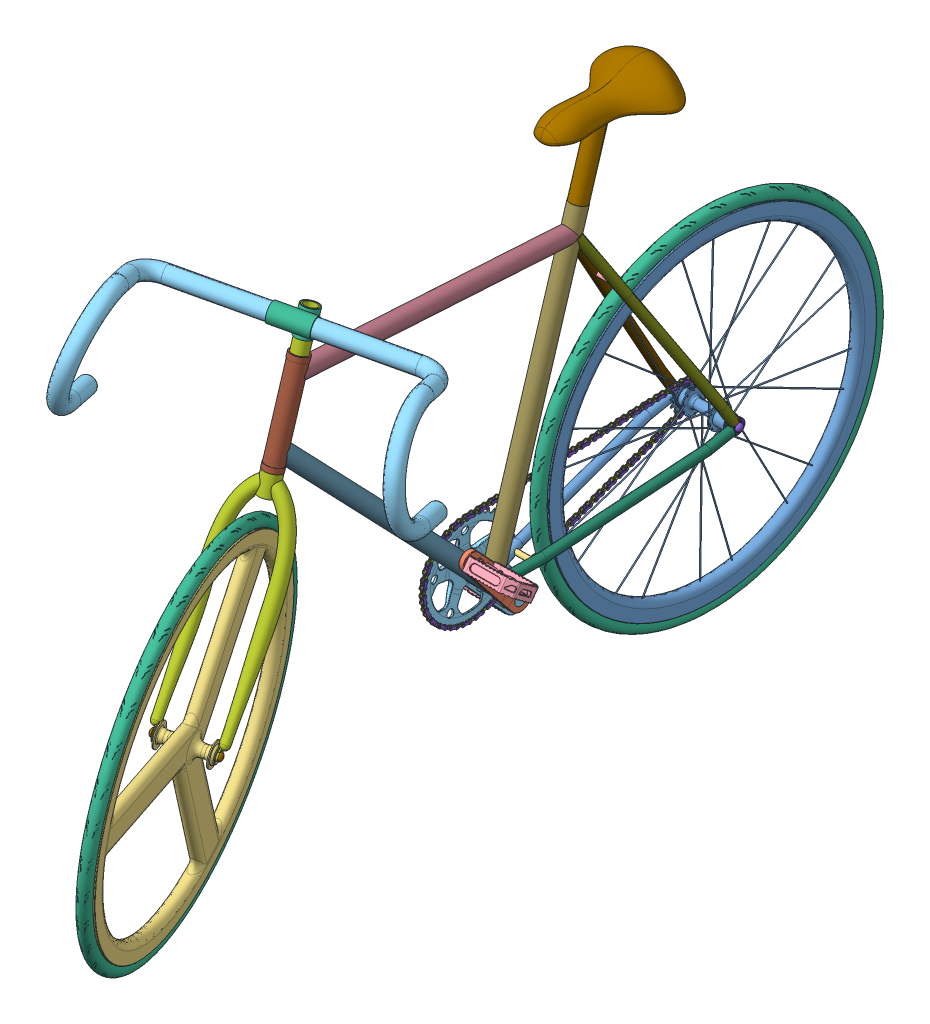
SolidWorks assembly Fixie, configuration Default. Lengths in mm.
Overall size (664.18 1172.49 1914.22).
126 component instances, 27 part files, 33 mates.
Components (placement in the parent):
- Copy of Back Wheel^Fixie-1: Copy of Back Wheel^Fixie [Default] at (-15.95 85.0139 -432.7378) x (1 0 0) z (0 -0.997869 -0.065253) size (100 658.88 658.88) (virtual)
- Copy of Crank 2^Fixie-1: Copy of Crank 2^Fixie [Default] at (48.55 125.8619 140.7881) x (0 0.660802 -0.75056) z (-1 0 0) size (45 210 26.78) (virtual)
- Copy of Front Wheel^Fixie-1: Copy of Front Wheel^Fixie [Default] at (21.1934 60.1847 648.9322) x (0.932997 -0.10522 -0.344158) z (0.342979 0.549615 0.761767) size (100 658.88 658.88) (virtual)
- Copy of Pedal 2^Fixie-1: Copy of Pedal 2^Fixie [Default] at (-152.95 -127.5952 -112.3364) x (0 0.808966 0.587856) z (1 0 0) size (80 25 117.5) (virtual)
- Copy of Sprocket 2^Fixie-1: Copy of Sprocket 2^Fixie [Default] at (-66.45 0 0) x (-1 0 0) z (0 -0.975768 0.218806) size (135 250.05 212.39) (virtual)
- Copy of Tire^Fixie-1: Copy of Tire^Fixie [Default] at (-15.95 85.0139 -432.7378) x (1 0 0) z (0 -0.101006 0.994886) size (24.5 700 700) (virtual)
- Copy of Tire^Fixie-2: Copy of Tire^Fixie [Default] at (21.1934 60.1847 648.9322) x (0.932997 -0.10522 -0.344158) z (0.359683 0.240759 0.901478) size (24.5 700 700) (virtual)
- Copy of fourche^Fixie-1: Copy of fourche^Fixie [Défaut<Brut d'usinage>] at (-16.45 376.3038 450.2354) x (0.932997 -0.10522 -0.344158) z (0.359883 0.272782 0.89223) size (141.09 668.83 129.54) (virtual)
- Copy of Pedal 2^Fixie-2: Copy of Pedal 2^Fixie [Default] at (120.05 127.5952 112.3364) x (0 0.589054 0.808094) z (-1 0 0) size (80 25 117.5) (virtual)
- Copy of Axe 2^Fixie-1: Copy of Axe 2^Fixie [Default] at (-16.45 85.0139 -432.7378) x (1 0 0) z (0 0.986418 0.164253) size (142 15 15) (virtual)
- Copy of Axe^Fixie-1: Copy of Axe^Fixie [Default] at (21.1934 60.1847 648.9322) x (-0.199209 0.645439 -0.737377) z (0.932997 -0.10522 -0.344158) size (15 15 115) (virtual)
- Copy of cadre^Fixie-1: Copy of cadre^Fixie [Défaut] at (-16.45 0 0) size (140 613.27 908.21) (virtual)
  - tube pedalier^Copy of cadre_Fixie-1: tube pedalier^Copy of cadre_Fixie [Défaut] at origin size (73 33 33) (virtual)
  - trou pour fourche^Copy of cadre_Fixie-2: trou pour fourche^Copy of cadre_Fixie [Défaut] at (0 502.9172 411.5258) x (0.998411 0.016475 0.053886) z (0 -0.956305 0.292372) size (35 35 185) (virtual)
  - tube de selle^Copy of cadre_Fixie-1: tube de selle^Copy of cadre_Fixie [Défaut] at (0 573.7829 -175.423) x (1 0 0) z (0 0.956305 -0.292372) size (32.9 32.9 600.3) (virtual)
  - tube de tete^Copy of cadre_Fixie-1: tube de tete^Copy of cadre_Fixie [Défaut] at (0 561.2509 393.6914) x (1 0 0) z (0 0.060491 0.998169) size (32.9 32.9 555.16) (virtual)
  - tube du bas^Copy of cadre_Fixie-3: tube du bas^Copy of cadre_Fixie [Défaut] at (0 447.1547 428.5741) x (-1 0 0) z (0 -0.721947 -0.691948) size (32.9 32.9 618.4) (virtual)
  - tube arriere bas^Copy of cadre_Fixie-2: tube arriere bas^Copy of cadre_Fixie [Défaut] at origin size (67.83 98.35 411.57) (virtual)
  - tube arriere haut^Copy of cadre_Fixie-1: tube arriere haut^Copy of cadre_Fixie [Défaut] at origin size (69.56 441.01 279.99) (virtual)
  - encoche roue^Copy of cadre_Fixie-7: encoche roue^Copy of cadre_Fixie [Défaut] at (61 85.0139 -432.7378) x (0 -0.852467 -0.522781) z (-1 0 0) size (54 61.43 6.25) (virtual)
  - Symétrietube arriere haut^Copy of cadre_Fixie-2: Symétrietube arriere haut^Copy of cadre_Fixie [Défaut] x (-1 0 0) z (0 0 -1) size (69.56 441.01 279.99) (virtual)
  - Symétrietube arriere bas^Copy of cadre_Fixie-3: Symétrietube arriere bas^Copy of cadre_Fixie [Défaut] x (-1 0 0) z (0 0 -1) size (67.83 98.35 411.57) (virtual)
  - Symétrieencoche roue^Copy of cadre_Fixie-8: Symétrieencoche roue^Copy of cadre_Fixie [Défaut] at (-61 85.0139 -432.7378) x (0 -0.852467 -0.522781) z (-1 0 0) size (54 61.43 6.25) (virtual)
  - tube consolider 1^Copy of cadre_Fixie-1: tube consolider 1^Copy of cadre_Fixie [Défaut] x (0 0 -1) z (1 0 0) size (10 10 30.38) (virtual)
  - tube consolider 2^Copy of cadre_Fixie-1: tube consolider 2^Copy of cadre_Fixie [Défaut] x (0 0 -1) z (1 0 0) size (10 10 34.39) (virtual)
- Copy of Guidon 2^Fixie-1: Copy of Guidon 2^Fixie [Défaut] at (6.8353 678.1903 421.0648) x (0.932997 -0.10522 -0.344158) z (0.023583 0.972124 -0.233276) size (595.69 286.25 238.07) (virtual)
- Copy of Potence 2^Fixie-1: Copy of Potence 2^Fixie [Défaut] at (6.8353 678.1903 421.0648) x (-0.359883 -0.272782 -0.89223) z (0.932997 -0.10522 -0.344158) size (98.9 64.61 70) (virtual)
- Copy of Inner Chain^Fixie-1: Copy of Inner Chain^Fixie [Default] at (-62.45 99.4001 -193.872) x (1 0 0) z (0 -0.042605 0.999092) size (5 8 20.8) (virtual)
- Copy of Outter Chain^Fixie-1: Copy of Outter Chain^Fixie [Default] at (-62.45 99.9453 -206.6574) x (1 0 0) z (0 -0.042605 0.999092) size (8.5 8 20.8) (virtual)
- Copy of Inner Chain^Fixie-52: Copy of Inner Chain^Fixie [Default] at (-62.45 100.4905 -219.4428) x (1 0 0) z (0 -0.042605 0.999092) size (5 8 20.8) (virtual)
- Copy of Inner Chain^Fixie-53: Copy of Inner Chain^Fixie [Default] at (-62.45 101.581 -245.0135) x (1 0 0) z (0 -0.042605 0.999092) size (5 8 20.8) (virtual)
- Copy of Inner Chain^Fixie-54: Copy of Inner Chain^Fixie [Default] at (-62.45 102.6714 -270.5843) x (1 0 0) z (0 -0.042605 0.999092) size (5 8 20.8) (virtual)
- Copy of Inner Chain^Fixie-55: Copy of Inner Chain^Fixie [Default] at (-62.45 103.7618 -296.155) x (1 0 0) z (0 -0.042605 0.999092) size (5 8 20.8) (virtual)
- Copy of Inner Chain^Fixie-56: Copy of Inner Chain^Fixie [Default] at (-62.45 104.8523 -321.7258) x (1 0 0) z (0 -0.042605 0.999092) size (5 8 20.8) (virtual)
- Copy of Inner Chain^Fixie-57: Copy of Inner Chain^Fixie [Default] at (-62.45 105.9427 -347.2966) x (1 0 0) z (0 -0.042605 0.999092) size (5 8 20.8) (virtual)
- Copy of Inner Chain^Fixie-58: Copy of Inner Chain^Fixie [Default] at (-62.45 107.0331 -372.8673) x (1 0 0) z (0 -0.042605 0.999092) size (5 8 20.8) (virtual)
- Copy of Inner Chain^Fixie-59: Copy of Inner Chain^Fixie [Default] at (-62.45 108.1235 -398.4381) x (1 0 0) z (0 -0.042605 0.999092) size (5 8 20.8) (virtual)
- Copy of Inner Chain^Fixie-60: Copy of Inner Chain^Fixie [Default] at (-62.45 109.214 -424.0088) x (1 0 0) z (0 -0.042605 0.999092) size (5 8 20.8) (virtual)
- Copy of Inner Chain^Fixie-61: Copy of Inner Chain^Fixie [Default] at (-62.45 103.2107 -447.9246) x (1 0 0) z (0 0.640753 0.767747) size (5 8 20.8) (virtual)
- Copy of Inner Chain^Fixie-62: Copy of Inner Chain^Fixie [Default] at (-62.45 80.7849 -456.059) x (1 0 0) z (0 0.983953 -0.178426) size (5 8 20.8) (virtual)
- Copy of Inner Chain^Fixie-63: Copy of Inner Chain^Fixie [Default] at (-62.45 62.2217 -440.7328) x (1 0 0) z (0 0.396262 -0.918137) size (5 8 20.8) (virtual)
- Copy of Inner Chain^Fixie-64: Copy of Inner Chain^Fixie [Default] at (-62.45 53.188 -416.796) x (1 0 0) z (0 0.338529 -0.940956) size (5 8 20.8) (virtual)
- Copy of Inner Chain^Fixie-65: Copy of Inner Chain^Fixie [Default] at (-62.45 44.5237 -392.7132) x (1 0 0) z (0 0.338529 -0.940956) size (5 8 20.8) (virtual)
- Copy of Inner Chain^Fixie-66: Copy of Inner Chain^Fixie [Default] at (-62.45 35.8594 -368.6303) x (1 0 0) z (0 0.338529 -0.940956) size (5 8 20.8) (virtual)
- Copy of Inner Chain^Fixie-67: Copy of Inner Chain^Fixie [Default] at (-62.45 27.195 -344.5475) x (1 0 0) z (0 0.338529 -0.940956) size (5 8 20.8) (virtual)
- Copy of Inner Chain^Fixie-68: Copy of Inner Chain^Fixie [Default] at (-62.45 18.5307 -320.4647) x (1 0 0) z (0 0.338529 -0.940956) size (5 8 20.8) (virtual)
- Copy of Inner Chain^Fixie-69: Copy of Inner Chain^Fixie [Default] at (-62.45 9.8664 -296.3818) x (1 0 0) z (0 0.338529 -0.940956) size (5 8 20.8) (virtual)
- Copy of Inner Chain^Fixie-70: Copy of Inner Chain^Fixie [Default] at (-62.45 1.2021 -272.299) x (1 0 0) z (0 0.338529 -0.940956) size (5 8 20.8) (virtual)
- Copy of Inner Chain^Fixie-71: Copy of Inner Chain^Fixie [Default] at (-62.45 -7.4622 -248.2162) x (1 0 0) z (0 0.338529 -0.940956) size (5 8 20.8) (virtual)
- Copy of Inner Chain^Fixie-72: Copy of Inner Chain^Fixie [Default] at (-62.45 -16.1265 -224.1334) x (1 0 0) z (0 0.338529 -0.940956) size (5 8 20.8) (virtual)
- Copy of Inner Chain^Fixie-73: Copy of Inner Chain^Fixie [Default] at (-62.45 -24.7908 -200.0505) x (1 0 0) z (0 0.338529 -0.940956) size (5 8 20.8) (virtual)
- Copy of Inner Chain^Fixie-74: Copy of Inner Chain^Fixie [Default] at (-62.45 -33.4551 -175.9677) x (1 0 0) z (0 0.338529 -0.940956) size (5 8 20.8) (virtual)
- Copy of Inner Chain^Fixie-75: Copy of Inner Chain^Fixie [Default] at (-62.45 -42.1195 -151.8849) x (1 0 0) z (0 0.338529 -0.940956) size (5 8 20.8) (virtual)
- Copy of Inner Chain^Fixie-76: Copy of Inner Chain^Fixie [Default] at (-62.45 -50.7838 -127.8021) x (1 0 0) z (0 0.338529 -0.940956) size (5 8 20.8) (virtual)
- Copy of Inner Chain^Fixie-77: Copy of Inner Chain^Fixie [Default] at (-62.45 -59.4481 -103.7192) x (1 0 0) z (0 0.338529 -0.940956) size (5 8 20.8) (virtual)
- Copy of Inner Chain^Fixie-78: Copy of Inner Chain^Fixie [Default] at (-62.45 -68.1124 -79.6364) x (1 0 0) z (0 0.338529 -0.940956) size (5 8 20.8) (virtual)
- Copy of Inner Chain^Fixie-79: Copy of Inner Chain^Fixie [Default] at (-62.45 -76.7767 -55.5536) x (1 0 0) z (0 0.338529 -0.940956) size (5 8 20.8) (virtual)
- Copy of Inner Chain^Fixie-80: Copy of Inner Chain^Fixie [Default] at (-62.45 -85.3565 -31.441) x (1 0 0) z (0 0.325323 -0.945603) size (5 8 20.8) (virtual)
- Copy of Inner Chain^Fixie-81: Copy of Inner Chain^Fixie [Default] at (-62.45 -90.5921 -6.4987) x (1 0 0) z (0 0.071552 -0.997437) size (5 8 20.8) (virtual)
- Copy of Inner Chain^Fixie-82: Copy of Inner Chain^Fixie [Default] at (-62.45 -88.8349 18.9082) x (1 0 0) z (0 -0.208183 -0.97809) size (5 8 20.8) (virtual)
- Copy of Inner Chain^Fixie-83: Copy of Inner Chain^Fixie [Default] at (-62.45 -80.093 42.8284) x (1 0 0) z (0 -0.471549 -0.88184) size (5 8 20.8) (virtual)
- Copy of Inner Chain^Fixie-84: Copy of Inner Chain^Fixie [Default] at (-62.45 -65.0537 63.3812) x (1 0 0) z (0 -0.69784 -0.716254) size (5 8 20.8) (virtual)
- Copy of Inner Chain^Fixie-85: Copy of Inner Chain^Fixie [Default] at (-62.45 -44.8995 78.9506) x (1 0 0) z (0 -0.869262 -0.494352) size (5 8 20.8) (virtual)
- Copy of Inner Chain^Fixie-86: Copy of Inner Chain^Fixie [Default] at (-62.45 -21.215 88.3124) x (1 0 0) z (0 -0.972337 -0.233581) size (5 8 20.8) (virtual)
- Copy of Inner Chain^Fixie-87: Copy of Inner Chain^Fixie [Default] at (-62.45 4.1376 90.7306) x (1 0 0) z (0 -0.998962 0.045555) size (5 8 20.8) (virtual)
- Copy of Inner Chain^Fixie-88: Copy of Inner Chain^Fixie [Default] at (-62.45 29.1648 86.015) x (1 0 0) z (0 -0.947042 0.32111) size (5 8 20.8) (virtual)
- Copy of Inner Chain^Fixie-89: Copy of Inner Chain^Fixie [Default] at (-62.45 51.8989 74.5363) x (1 0 0) z (0 -0.82066 0.571417) size (5 8 20.8) (virtual)
- Copy of Inner Chain^Fixie-90: Copy of Inner Chain^Fixie [Default] at (-62.45 70.5524 57.1972) x (1 0 0) z (0 -0.629752 0.776796) size (5 8 20.8) (virtual)
- Copy of Inner Chain^Fixie-91: Copy of Inner Chain^Fixie [Default] at (-62.45 83.6587 35.3609) x (1 0 0) z (0 -0.38933 0.921098) size (5 8 20.8) (virtual)
- Copy of Inner Chain^Fixie-92: Copy of Inner Chain^Fixie [Default] at (-62.45 90.1872 10.7443) x (1 0 0) z (0 -0.118296 0.992978) size (5 8 20.8) (virtual)
- Copy of Inner Chain^Fixie-93: Copy of Inner Chain^Fixie [Default] at (-62.45 91.7633 -14.7873) x (1 0 0) z (0 -0.042605 0.999092) size (5 8 20.8) (virtual)
- Copy of Inner Chain^Fixie-94: Copy of Inner Chain^Fixie [Default] at (-62.45 92.8538 -40.3581) x (1 0 0) z (0 -0.042605 0.999092) size (5 8 20.8) (virtual)
- Copy of Inner Chain^Fixie-95: Copy of Inner Chain^Fixie [Default] at (-62.45 93.9442 -65.9288) x (1 0 0) z (0 -0.042605 0.999092) size (5 8 20.8) (virtual)
- Copy of Inner Chain^Fixie-96: Copy of Inner Chain^Fixie [Default] at (-62.45 95.0346 -91.4996) x (1 0 0) z (0 -0.042605 0.999092) size (5 8 20.8) (virtual)
- Copy of Inner Chain^Fixie-97: Copy of Inner Chain^Fixie [Default] at (-62.45 96.125 -117.0704) x (1 0 0) z (0 -0.042605 0.999092) size (5 8 20.8) (virtual)
- Copy of Inner Chain^Fixie-98: Copy of Inner Chain^Fixie [Default] at (-62.45 97.2155 -142.6411) x (1 0 0) z (0 -0.042605 0.999092) size (5 8 20.8) (virtual)
- Copy of Outter Chain^Fixie-52: Copy of Outter Chain^Fixie [Default] at (-62.45 101.0358 -232.2281) x (1 0 0) z (0 -0.042605 0.999092) size (8.5 8 20.8) (virtual)
- Copy of Outter Chain^Fixie-53: Copy of Outter Chain^Fixie [Default] at (-62.45 102.1262 -257.7989) x (1 0 0) z (0 -0.042605 0.999092) size (8.5 8 20.8) (virtual)
- Copy of Outter Chain^Fixie-54: Copy of Outter Chain^Fixie [Default] at (-62.45 103.2166 -283.3697) x (1 0 0) z (0 -0.042605 0.999092) size (8.5 8 20.8) (virtual)
- Copy of Outter Chain^Fixie-55: Copy of Outter Chain^Fixie [Default] at (-62.45 104.307 -308.9404) x (1 0 0) z (0 -0.042605 0.999092) size (8.5 8 20.8) (virtual)
- Copy of Outter Chain^Fixie-56: Copy of Outter Chain^Fixie [Default] at (-62.45 105.3975 -334.5112) x (1 0 0) z (0 -0.042605 0.999092) size (8.5 8 20.8) (virtual)
- Copy of Outter Chain^Fixie-57: Copy of Outter Chain^Fixie [Default] at (-62.45 106.4879 -360.0819) x (1 0 0) z (0 -0.042605 0.999092) size (8.5 8 20.8) (virtual)
- Copy of Outter Chain^Fixie-58: Copy of Outter Chain^Fixie [Default] at (-62.45 107.5783 -385.6527) x (1 0 0) z (0 -0.042605 0.999092) size (8.5 8 20.8) (virtual)
- Copy of Outter Chain^Fixie-59: Copy of Outter Chain^Fixie [Default] at (-62.45 108.6687 -411.2235) x (1 0 0) z (0 -0.042605 0.999092) size (8.5 8 20.8) (virtual)
- Copy of Outter Chain^Fixie-60: Copy of Outter Chain^Fixie [Default] at (-62.45 108.3985 -436.7069) x (1 0 0) z (0 0.170044 0.985436) size (8.5 8 20.8) (virtual)
- Copy of Outter Chain^Fixie-61: Copy of Outter Chain^Fixie [Default] at (-62.45 93.0958 -455.0188) x (1 0 0) z (0 0.940068 0.340986) size (8.5 8 20.8) (virtual)
- Copy of Outter Chain^Fixie-62: Copy of Outter Chain^Fixie [Default] at (-62.45 69.6231 -450.7624) x (1 0 0) z (0 0.760484 -0.649357) size (8.5 8 20.8) (virtual)
- Copy of Outter Chain^Fixie-63: Copy of Outter Chain^Fixie [Default] at (-62.45 57.5201 -428.8374) x (1 0 0) z (0 0.338529 -0.940956) size (8.5 8 20.8) (virtual)
- Copy of Outter Chain^Fixie-64: Copy of Outter Chain^Fixie [Default] at (-62.45 48.8558 -404.7546) x (1 0 0) z (0 0.338529 -0.940956) size (8.5 8 20.8) (virtual)
- Copy of Outter Chain^Fixie-65: Copy of Outter Chain^Fixie [Default] at (-62.45 40.1915 -380.6717) x (1 0 0) z (0 0.338529 -0.940956) size (8.5 8 20.8) (virtual)
- Copy of Outter Chain^Fixie-66: Copy of Outter Chain^Fixie [Default] at (-62.45 31.5272 -356.5889) x (1 0 0) z (0 0.338529 -0.940956) size (8.5 8 20.8) (virtual)
- Copy of Outter Chain^Fixie-67: Copy of Outter Chain^Fixie [Default] at (-62.45 22.8629 -332.5061) x (1 0 0) z (0 0.338529 -0.940956) size (8.5 8 20.8) (virtual)
- Copy of Outter Chain^Fixie-68: Copy of Outter Chain^Fixie [Default] at (-62.45 14.1986 -308.4233) x (1 0 0) z (0 0.338529 -0.940956) size (8.5 8 20.8) (virtual)
- Copy of Outter Chain^Fixie-69: Copy of Outter Chain^Fixie [Default] at (-62.45 5.5343 -284.3404) x (1 0 0) z (0 0.338529 -0.940956) size (8.5 8 20.8) (virtual)
- Copy of Outter Chain^Fixie-70: Copy of Outter Chain^Fixie [Default] at (-62.45 -3.1301 -260.2576) x (1 0 0) z (0 0.338529 -0.940956) size (8.5 8 20.8) (virtual)
- Copy of Outter Chain^Fixie-71: Copy of Outter Chain^Fixie [Default] at (-62.45 -11.7944 -236.1748) x (1 0 0) z (0 0.338529 -0.940956) size (8.5 8 20.8) (virtual)
- Copy of Outter Chain^Fixie-72: Copy of Outter Chain^Fixie [Default] at (-62.45 -20.4587 -212.092) x (1 0 0) z (0 0.338529 -0.940956) size (8.5 8 20.8) (virtual)
- Copy of Outter Chain^Fixie-73: Copy of Outter Chain^Fixie [Default] at (-62.45 -29.123 -188.0091) x (1 0 0) z (0 0.338529 -0.940956) size (8.5 8 20.8) (virtual)
- Copy of Outter Chain^Fixie-74: Copy of Outter Chain^Fixie [Default] at (-62.45 -37.7873 -163.9263) x (1 0 0) z (0 0.338529 -0.940956) size (8.5 8 20.8) (virtual)
- Copy of Outter Chain^Fixie-75: Copy of Outter Chain^Fixie [Default] at (-62.45 -46.4516 -139.8435) x (1 0 0) z (0 0.338529 -0.940956) size (8.5 8 20.8) (virtual)
- Copy of Outter Chain^Fixie-76: Copy of Outter Chain^Fixie [Default] at (-62.45 -55.1159 -115.7606) x (1 0 0) z (0 0.338529 -0.940956) size (8.5 8 20.8) (virtual)
- Copy of Outter Chain^Fixie-77: Copy of Outter Chain^Fixie [Default] at (-62.45 -63.7802 -91.6778) x (1 0 0) z (0 0.338529 -0.940956) size (8.5 8 20.8) (virtual)
- Copy of Outter Chain^Fixie-78: Copy of Outter Chain^Fixie [Default] at (-62.45 -72.4446 -67.595) x (1 0 0) z (0 0.338529 -0.940956) size (8.5 8 20.8) (virtual)
- Copy of Outter Chain^Fixie-79: Copy of Outter Chain^Fixie [Default] at (-62.45 -81.1089 -43.5122) x (1 0 0) z (0 0.338529 -0.940956) size (8.5 8 20.8) (virtual)
- Copy of Outter Chain^Fixie-80: Copy of Outter Chain^Fixie [Default] at (-62.45 -88.7862 -19.1357) x (1 0 0) z (0 0.210688 -0.977553) size (8.5 8 20.8) (virtual)
- Copy of Outter Chain^Fixie-81: Copy of Outter Chain^Fixie [Default] at (-62.45 -90.6084 6.2666) x (1 0 0) z (0 -0.068997 -0.997617) size (8.5 8 20.8) (virtual)
- Copy of Outter Chain^Fixie-82: Copy of Outter Chain^Fixie [Default] at (-62.45 -85.3065 31.1762) x (1 0 0) z (0 -0.343256 -0.939242) size (8.5 8 20.8) (virtual)
- Copy of Outter Chain^Fixie-83: Copy of Outter Chain^Fixie [Default] at (-62.45 -73.2973 53.6346) x (1 0 0) z (0 -0.590527 -0.807018) size (8.5 8 20.8) (virtual)
- Copy of Outter Chain^Fixie-84: Copy of Outter Chain^Fixie [Default] at (-62.45 -55.525 71.8758) x (1 0 0) z (0 -0.791367 -0.611341) size (8.5 8 20.8) (virtual)
- Copy of Outter Chain^Fixie-85: Copy of Outter Chain^Fixie [Default] at (-62.45 -33.387 84.4658) x (1 0 0) z (0 -0.929985 -0.367597) size (8.5 8 20.8) (virtual)
- Copy of Outter Chain^Fixie-86: Copy of Outter Chain^Fixie [Default] at (-62.45 -8.6239 90.4145) x (1 0 0) z (0 -0.995482 -0.094951) size (8.5 8 20.8) (virtual)
- Copy of Outter Chain^Fixie-87: Copy of Outter Chain^Fixie [Default] at (-62.45 16.8173 89.2544) x (1 0 0) z (0 -0.982708 0.185162) size (8.5 8 20.8) (virtual)
- Copy of Outter Chain^Fixie-88: Copy of Outter Chain^Fixie [Default] at (-62.45 40.9362 81.0765) x (1 0 0) z (0 -0.892668 0.450715) size (8.5 8 20.8) (virtual)
- Copy of Outter Chain^Fixie-89: Copy of Outter Chain^Fixie [Default] at (-62.45 61.8364 66.5238) x (1 0 0) z (0 -0.73244 0.680831) size (8.5 8 20.8) (virtual)
- Copy of Outter Chain^Fixie-90: Copy of Outter Chain^Fixie [Default] at (-62.45 77.8747 46.7407) x (1 0 0) z (0 -0.514624 0.857416) size (8.5 8 20.8) (virtual)
- Copy of Outter Chain^Fixie-91: Copy of Outter Chain^Fixie [Default] at (-62.45 87.79 23.2825) x (1 0 0) z (0 -0.256345 0.966585) size (8.5 8 20.8) (virtual)
- Copy of Outter Chain^Fixie-92: Copy of Outter Chain^Fixie [Default] at (-62.45 91.2174 -2.002) x (1 0 0) z (0 -0.042717 0.999087) size (8.5 8 20.8) (virtual)
- Copy of Outter Chain^Fixie-93: Copy of Outter Chain^Fixie [Default] at (-62.45 92.3085 -27.5727) x (1 0 0) z (0 -0.042605 0.999092) size (8.5 8 20.8) (virtual)
- Copy of Outter Chain^Fixie-94: Copy of Outter Chain^Fixie [Default] at (-62.45 93.399 -53.1435) x (1 0 0) z (0 -0.042605 0.999092) size (8.5 8 20.8) (virtual)
- Copy of Outter Chain^Fixie-95: Copy of Outter Chain^Fixie [Default] at (-62.45 94.4894 -78.7142) x (1 0 0) z (0 -0.042605 0.999092) size (8.5 8 20.8) (virtual)
- Copy of Outter Chain^Fixie-96: Copy of Outter Chain^Fixie [Default] at (-62.45 95.5798 -104.285) x (1 0 0) z (0 -0.042605 0.999092) size (8.5 8 20.8) (virtual)
- Copy of Outter Chain^Fixie-97: Copy of Outter Chain^Fixie [Default] at (-62.45 96.6702 -129.8557) x (1 0 0) z (0 -0.042605 0.999092) size (8.5 8 20.8) (virtual)
- Copy of Outter Chain^Fixie-98: Copy of Outter Chain^Fixie [Default] at (-62.45 97.7607 -155.4265) x (1 0 0) z (0 -0.042605 0.999092) size (8.5 8 20.8) (virtual)
- Copy of Inner Chain^Fixie-99: Copy of Inner Chain^Fixie [Default] at (-62.45 98.3059 -168.2119) x (1 0 0) z (0 -0.042605 0.999092) size (5 8 20.8) (virtual)
- Copy of Outter Chain^Fixie-99: Copy of Outter Chain^Fixie [Default] at (-62.45 98.8511 -180.9973) x (1 0 0) z (0 -0.042605 0.999092) size (8.5 8 20.8) (virtual)
- Copy of selle^Fixie-1: Copy of selle^Fixie [Défaut] at (-16.4182 711.7295 -219.3745) x (-0.999825 -0.005469 -0.017888) z (0.01779 0.017501 -0.999689) size (178.5 284.8 238.49) (virtual)
Mates (geometry in assembly coordinates):
- Concentric3: concentric anti-aligned: line of Copy of Pedal 2^Fixie-1 through (-101.45 -127.5952 -112.3364) axis (1 0 0); cylinder of Sprocket 2-1 through (110.8101 -127.5952 -112.3364) axis (-1 0 0) radius 6.25
- Coincident1: coincident aligned: plane of Copy of Pedal 2^Fixie-1 through (-81.45 -132.6512 -116.0105) normal (1 0 0); plane of Sprocket 2-1 through (-81.45 -127.4157 -82.2008) normal (1 0 0)
- Concentric5: concentric anti-aligned: cylinder of Copy of Back Wheel^Fixie-1 through (-64.45 85.0139 -432.7378) axis (1 0 0) radius 329.44; cylinder of Tire-1 through (-70.2626 85.0139 -432.7378) axis (-1 0 0) radius 325.44
- Coincident4: coincident anti-aligned: plane of Copy of Back Wheel^Fixie-1 through (-6.95 85.0139 -432.7378) normal (-1 0 0); plane of Tire-1 through (-6.95 410.7793 -399.6643) normal (1 0 0)
- Concentric6: concentric aligned: cylinder of Copy of Front Wheel^Fixie-1 through (-24.5235 65.3405 665.796) axis (-0.932997 0.10522 0.344158) radius 329.44; cylinder of Tire-2 through (-29.4802 65.8995 667.6243) axis (-0.932997 0.10522 0.344158) radius 325.44
- Coincident6: coincident anti-aligned: plane of Copy of Front Wheel^Fixie-1 through (29.5903 59.2377 645.8348) normal (-0.932997 0.10522 0.344158); plane of Tire-2 through (33.5177 375.173 559.8906) normal (0.932997 -0.10522 -0.344158)
- Concentric12: concentric aligned: cylinder of Copy of Front Wheel^Fixie-1 through (-23.5905 65.2352 665.4518) axis (-0.932997 0.10522 0.344158) radius 8.5; cylinder of fourche-1 through (87.0098 52.7622 624.6543) axis (-0.932997 0.10522 0.344158) radius 6
- Coincident33: coincident aligned: plane of Copy of Crank 2^Fixie-1 through (43.55 26.1628 -6.9435) normal (1 0 0); plane of Sprocket 2-1 through (43.55 0 0) normal (1 0 0)
- Concentric22: concentric aligned: cylinder of Copy of Crank 2^Fixie-1 through (284.1603 0 0) axis (-1 0 0) radius 12; cylinder of Sprocket 2-1 through (43.55 0 0) axis (-1 0 0) radius 12
- Parallel8: parallel anti-aligned: plane of Copy of Crank 2^Fixie-1 through (56.9284 115.3712 71.5967) normal (0.992278 -0.093095 -0.081962); plane of Sprocket 2-1 through (-77.9172 -36.3454 -2.0213) normal (-0.992278 0.093095 0.081962)
- Concentric23: concentric aligned: cylinder of Copy of Crank 2^Fixie-1 through (284.1603 127.5952 112.3364) axis (-1 0 0) radius 6.25; cylinder of Pedal 2-2 through (48.55 127.5952 112.3364) axis (-1 0 0) radius 6.25
- Coincident35: coincident aligned: plane of Copy of Crank 2^Fixie-1 through (48.55 155.598 107.0129) normal (-1 0 0); plane of Pedal 2-2 through (48.55 123.9136 107.2858) normal (-1 0 0)
- Concentric26: concentric anti-aligned: cylinder of Copy of fourche^Fixie-1 through (87.0098 52.7622 624.6543) axis (-0.932997 0.10522 0.344158) radius 6; cylinder of Axe-1 through (74.8407 54.1346 629.1431) axis (0.932997 -0.10522 -0.344158) radius 6
- Width2: width anti-aligned: plane of Copy of Axe^Fixie-1 through (72.4236 60.3346 635.2231) normal (-0.932997 0.10522 0.344158); plane of Front Wheel-1 through (-25.5411 71.3827 671.3598) normal (0.932997 -0.10522 -0.344158); plane of Axe-1 through (66.4807 65.2833 624.8633) normal (0.932997 -0.10522 -0.344158); plane of Front Wheel-1 through (-26.819 75.8052 659.2791) normal (-0.932997 0.10522 0.344158)
- Concentric27: concentric anti-aligned: cylinder of Copy of fourche^Fixie-1 through (-16.45 663.6836 362.3746) axis (0 -0.956305 0.292372) radius 12.084; cylinder of Cadre-1/trou pour fourche^Cadre-2 through (-16.45 414.459 438.5702) axis (0 0.956305 -0.292372) radius 14.3
- Coincident36: coincident anti-aligned: plane of Copy of fourche^Fixie-1 through (0.1303 427.025 479.6718) normal (0 0.956305 -0.292372); plane of Cadre-1/trou pour fourche^Cadre-2 through (-16.45 414.459 438.5702) normal (0 -0.956305 0.292372)
- Concentric29: concentric aligned: circle of Cadre-1/tube pedalier^Cadre-1
- Concentric30: concentric aligned: circle of Cadre-1/tube de selle^Cadre-1
- Concentric31: concentric aligned: cylinder of Copy of Sprocket 2^Fixie-1 through (43.55 0 0) axis (-1 0 0) radius 12; cylinder of Cadre-1/tube pedalier^Cadre-1 through (20.05 0 0) axis (-1 0 0) radius 14.3
- Concentric32: concentric anti-aligned: cylinder of Copy of fourche^Fixie-1 through (-16.45 663.6836 362.3746) axis (0 -0.956305 0.292372) radius 14.3; cylinder of Potence 2-1 through (-16.45 615.8684 376.9932) axis (0 0.956305 -0.292372) radius 14.3
- Coincident39: coincident aligned: plane of Copy of fourche^Fixie-1 through (-16.45 663.6836 362.3746) normal (0 0.956305 -0.292372); plane of Potence 2-1 through (-16.45 663.6836 362.3746) normal (0 0.956305 -0.292372)
- Concentric33: concentric aligned: cylinder of Copy of Guidon 2^Fixie-1 through (6.8353 678.1903 421.0648) axis (0.932997 -0.10522 -0.344158) radius 15.9; cylinder of Potence 2-1 through (-25.8196 681.873 433.1104) axis (0.932997 -0.10522 -0.344158) radius 15.9
- ProfileCenter1: profile center = 165 mm aligned: circle of Guidon 2-1; plane of Potence 2-1 through (39.4902 674.5076 409.0193) normal (0.932997 -0.10522 -0.344158)
- Concentric34: concentric anti-aligned: cylinder of Copy of Axe 2^Fixie-1 through (-87.45 85.0139 -432.7378) axis (-1 0 0) radius 6; cylinder of Cadre-1/encoche roue^Cadre-7 through (42.05 85.0139 -432.7378) axis (1 0 0) radius 6
- Concentric35: concentric aligned: cylinder of Copy of Back Wheel^Fixie-1 through (-64.45 85.0139 -432.7378) axis (-1 0 0) radius 6; cylinder of Axe 2-1 through (-87.45 85.0139 -432.7378) axis (-1 0 0) radius 6
- Width3: width anti-aligned: plane of Copy of Axe 2^Fixie-1 through (48.3 77.6157 -433.9697) normal (-1 0 0); plane of Axe 2-1 through (-81.2 77.6157 -433.9697) normal (1 0 0); plane of Back Wheel-1 through (33.55 84.1003 -418.7676) normal (1 0 0); plane of Back Wheel-1 through (-66.45 84.1003 -418.7676) normal (-1 0 0)
- Width5: width anti-aligned: plane of Cadre-1/tube pedalier^Cadre-1 through (20.05 0 0) normal (1 0 0); plane of Cadre-1/tube pedalier^Cadre-1 through (-52.95 0 0) normal (-1 0 0); plane of Crank 2-1 through (33.55 26.1628 -6.9435) normal (-1 0 0); plane of Sprocket 2-1 through (-66.45 0 0) normal (1 0 0)
- GearMate2: gear = 45 : 12 mm: circle of Back Wheel-1; circle of Sprocket 2-1
- Coincident40: coincident anti-aligned: plane of Copy of fourche^Fixie-1 through (32.5324 370.7798 432.1671) normal (0.932997 -0.10522 -0.344158); plane of Axe-1 through (72.4236 60.3346 635.2231) normal (-0.932997 0.10522 0.344158)
- Coincident41: coincident anti-aligned: plane of Copy of Axe 2^Fixie-1 through (-81.2 77.6157 -433.9697) normal (1 0 0); plane of cadre-1/Symétrieencoche roue^cadre-8 through (-81.2 85.0139 -432.7378) normal (-1 0 0)
- Concentric36: concentric aligned: cylinder of Copy of cadre^Fixie-1/tube de selle^cadre-1 through (-16.45 -15.78 4.8244) axis (0 0.956305 -0.292372) radius 15.55; cylinder of selle-1 through (-16.45 487.7154 -149.1096) axis (0 0.956305 -0.292372) radius 16
- ProfileCenter2: profile center = 150 mm anti-aligned: plane of selle-1 through (-16.45 717.2286 -219.2788) normal (0 -0.956305 0.292372); plane of cadre-1/tube de selle^cadre-1 through (-16.45 573.7829 -175.423) normal (0 0.956305 -0.292372)
- Parallel9: parallel aligned: cylinder of Copy of fourche^Fixie-1 through (65.4553 55.2198 632.4244) axis (0.932997 -0.10522 -0.344158) radius 8; cylinder of Guidon 2-1 through (6.8353 678.1903 421.0648) axis (0.932997 -0.10522 -0.344158) radius 15.9
